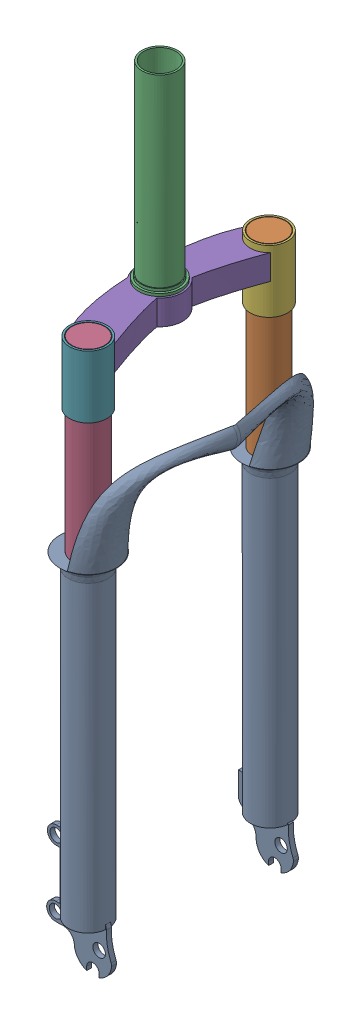
SolidWorks assembly bakfiets front fork, configuration Default. Lengths in mm.
Overall size (82.92 587.14 191.8).
5 component instances, 4 part files, 7 mates.
Components (placement in the parent):
- front fork-1: front fork [Default] at (241.3379 -61.9263 -219.1868) size (80.01 364.03 191.8)
- front fork two rod-1: front fork two rod [Default] at (240.4022 267.0737 -365.1838) size (26.23 150 26.23)
- top rod fork-1: top rod fork [Default] at (225.8703 337.0737 -292.0891) size (33.5 152.24 33.5)
- front fork two rod-2: front fork two rod [Default] at (241.3379 267.0737 -219.1868) size (26.23 150 26.23)
- 3 hole connecting part-2: 3 hole connecting part [Default] at (241.3379 292.0737 -219.1868) x (-0.006409 0 -0.999979) z (0 1 0) size (176 48.25 50)
Mates (geometry in assembly coordinates):
- Concentric8: concentric aligned: circle of front fork two rod-1; circle of 3 prong part-2
- Coincident4: coincident aligned: plane of front fork two rod-1 through (240.4022 342.0737 -365.1838) normal (0 1 0); plane of 3 prong part-2 through (240.4022 342.0737 -365.1838) normal (0 1 0)
- Coincident7: coincident aligned: circle of top rod fork-1; circle of 3 prong part-2
- Concentric11: concentric anti-aligned: circle of front fork-1; circle of front fork two rod-2
- Coincident8: coincident anti-aligned: plane of front fork-1 through (241.3379 192.0737 -219.1868) normal (0 1 0); plane of front fork two rod-2 through (241.3379 192.0737 -219.1868) normal (0 -1 0)
- Coincident9: coincident aligned: circle of front fork two rod-2; plane of 3 prong part-2 through (241.3379 342.0737 -219.1868) normal (0 1 0)
- Concentric12: concentric aligned: cylinder of front fork two rod-2 through (241.3379 342.0737 -219.1868) axis (0 -1 0) radius 13.115; cylinder of 3 prong part-2 through (241.3379 342.0737 -219.1868) axis (0 -1 0) radius 13.5
